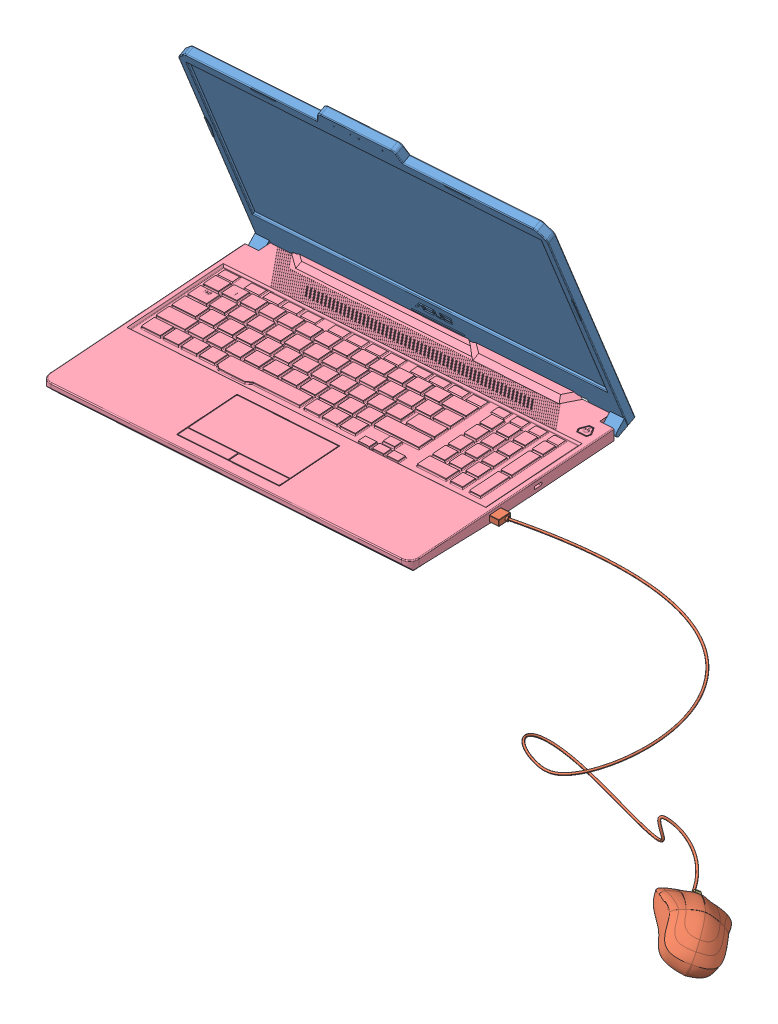
SolidWorks assembly 电脑组合1, configuration Default. Lengths in mm.
Overall size (912.49 361.59 550.52).
5 component instances, 4 part files, 0 mates.
Components (placement in the parent):
- 电脑组合1.STEP-1: 电脑组合1.STEP [Default] at origin size (912.49 361.59 550.52)
  - ________.STEP-1: ________.STEP [默认] at (-465.2106 26.9312 156.7097) x (0.997525 0 -0.070315) z (-0.027287 -0.921629 -0.387112) size (387 24.14 272)
  - ____.STEP-1: ____.STEP [默认] at (368.0951 -68.9531 517.0459) x (0.701066 0 0.713096) z (-0.646638 0.421554 0.635729) size (529.74 79.72 219.49)
  - ________-0.STEP-1: ________-0.STEP [默认] at (349.781 -54.9386 489.1245) x (-0.651435 -0.738782 -0.172725) z (-0.646638 0.421554 0.635729) size (17.82 17.82 5)
  - ____________.STEP-1: ____________.STEP [默认] at (-271.7877 0 316.3908) x (0.997525 0 -0.070315) z (0.070315 0 0.997525) size (387 27 259)
